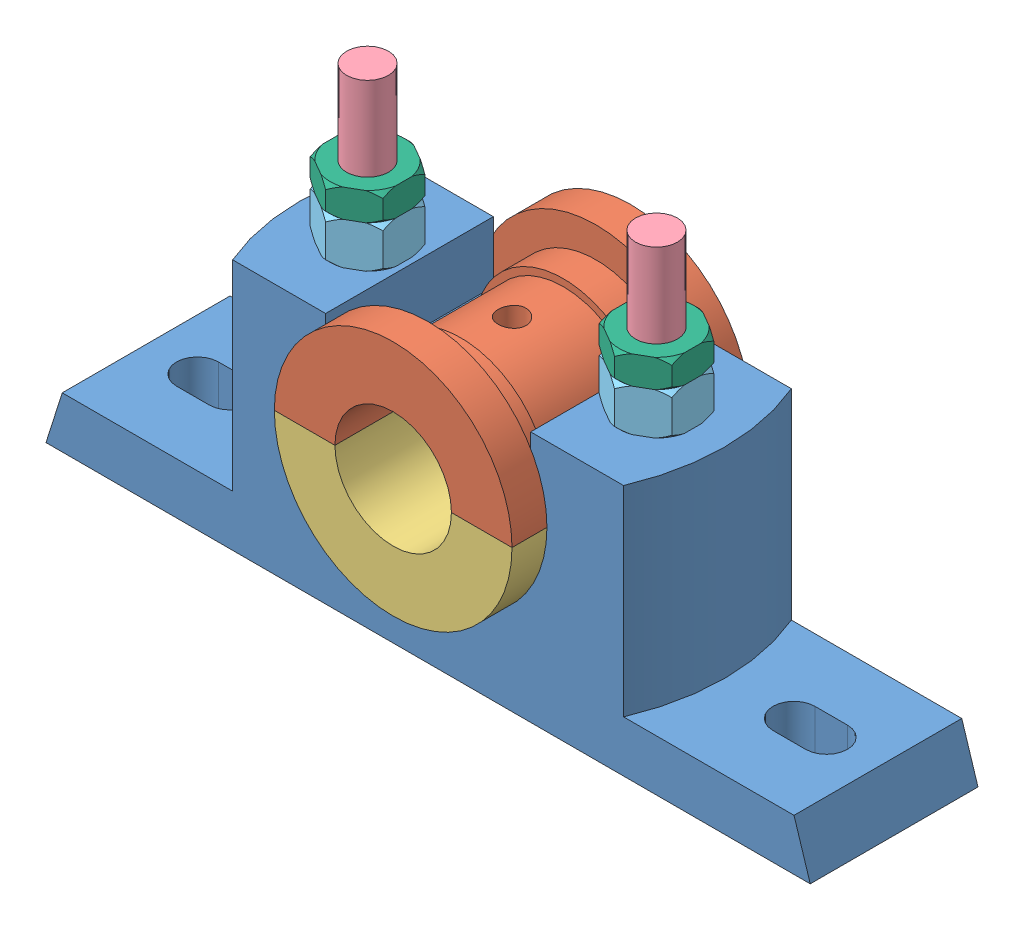
SolidWorks assembly Assem1done, configuration Default. Lengths in mm.
Overall size (164 87 51).
9 component instances, 6 part files, 18 mates.
Components (placement in the parent):
- asm22-1: asm22 [Default] at (54.4693 60.7091 128.001) size (164 54 36)
- asm33-1: asm33 [Default] at (54.4693 98.7091 128.001) x (0 0 1) z (0 1 0) size (51 51 25.5)
- asm44-1: asm44 [Default] at (54.4693 98.7091 128.001) x (0 0 1) z (0 1 0) size (51 51 25.5)
- asm55-1: asm55 [Default] at (23.4682 71.7091 128.001) x (0 1 0) z (-1 0 0) size (82 19 19)
- asm66-2: asm66 [Default] at (23.4682 119.2091 128.001) x (1 0 0) z (0 -1 0) size (15.59 18 9)
- asm77-1: asm77 [Default] at (23.4682 126.7091 128.001) x (1 0 0) z (0 -1 0) size (15.59 18 6)
- asm55-3: asm55 [Default] at (85.4703 71.7091 128.001) x (0 1 0) z (0 0 1) size (82 19 19)
- asm66-3: asm66 [Default] at (85.4703 119.2091 128.001) x (1 0 0) z (0 -1 0) size (15.59 18 9)
- asm77-2: asm77 [Default] at (85.4703 126.7091 128.001) x (1 0 0) z (0 -1 0) size (15.59 18 6)
Mates (geometry in assembly coordinates):
- Concentric1: concentric anti-aligned: cylinder of asm22-1 through (54.4693 60.7091 128.001) axis (0 -1 0) radius 3; cylinder of asm44-1 through (54.4693 75.2091 128.001) axis (0 1 0) radius 3
- Concentric2: concentric anti-aligned: cylinder of asm22-1 through (54.4693 98.7091 146.001) axis (0 0 -1) radius 19; cylinder of asm44-1 through (54.4693 98.7091 102.501) axis (0 0 1) radius 12.5
- Coincident1: coincident anti-aligned: plane of asm33-1 through (54.4693 98.7091 128.001) normal (0 -1 0); plane of asm44-1 through (54.4693 98.7091 128.001) normal (0 1 0)
- Concentric3: concentric anti-aligned: cylinder of asm33-1 through (54.4693 98.7091 98.0792) axis (0 0 -1) radius 17.5; cylinder of asm44-1 through (54.4693 98.7091 102.501) axis (0 0 1) radius 12.5
- Concentric5: concentric anti-aligned: cylinder of asm22-1 through (23.4682 71.7091 128.001) axis (0 1 0) radius 4.5; cylinder of asm55-1 through (23.4682 147.7091 128.001) axis (0 -1 0) radius 4.5
- Coincident4: coincident anti-aligned: plane of asm22-1 through (54.4693 71.7091 128.001) normal (0 -1 0); plane of asm55-1 through (23.4682 71.7091 128.001) normal (0 1 0)
- Coincident10: coincident: plane of asm22-1 through (13.9693 71.7091 118.501) normal (0 0 1); line of asm55-1 through (13.9682 65.7091 118.501) axis (1 0 0)
- Coincident11: coincident aligned: plane of asm33-1 through (54.4693 98.7091 102.501) normal (0 0 -1); plane of asm44-1 through (54.4693 98.7091 102.501) normal (0 0 -1)
- Concentric7: concentric anti-aligned: cylinder of asm55-1 through (23.4682 147.7091 128.001) axis (0 -1 0) radius 4.5; cylinder of asm66-2 through (23.4682 114.7091 128.001) axis (0 1 0) radius 4.5
- Coincident12: coincident anti-aligned: plane of asm22-1 through (4.4693 114.7091 146.001) normal (0 1 0); plane of asm66-2 through (23.4682 114.7091 128.001) normal (0 -1 0)
- Concentric8: concentric anti-aligned: cylinder of asm55-1 through (23.4682 147.7091 128.001) axis (0 -1 0) radius 4.5; cylinder of asm77-1 through (23.4682 123.7091 128.001) axis (0 1 0) radius 4.5
- Coincident13: coincident anti-aligned: plane of asm66-2 through (23.4682 123.7091 128.001) normal (0 1 0); plane of asm77-1 through (23.4682 123.7091 128.001) normal (0 -1 0)
- Concentric9: concentric anti-aligned: cylinder of asm22-1 through (85.4703 71.7091 128.001) axis (0 1 0) radius 4.5; cylinder of asm55-3 through (85.4703 147.7091 128.001) axis (0 -1 0) radius 4.5
- Coincident14: coincident anti-aligned: plane of asm22-1 through (54.4693 71.7091 128.001) normal (0 -1 0); plane of asm55-3 through (85.4703 71.7091 128.001) normal (0 1 0)
- Concentric10: concentric anti-aligned: cylinder of asm55-3 through (85.4703 147.7091 128.001) axis (0 -1 0) radius 4.5; cylinder of asm66-3 through (85.4703 114.7091 128.001) axis (0 1 0) radius 4.5
- Coincident15: coincident anti-aligned: plane of asm22-1 through (104.4693 114.7091 146.001) normal (0 1 0); plane of asm66-3 through (85.4703 114.7091 128.001) normal (0 -1 0)
- Concentric11: concentric anti-aligned: cylinder of asm55-3 through (85.4703 147.7091 128.001) axis (0 -1 0) radius 4.5; cylinder of asm77-2 through (85.4703 123.7091 128.001) axis (0 1 0) radius 4.5
- Coincident16: coincident anti-aligned: plane of asm66-3 through (85.4703 123.7091 128.001) normal (0 1 0); plane of asm77-2 through (85.4703 123.7091 128.001) normal (0 -1 0)
